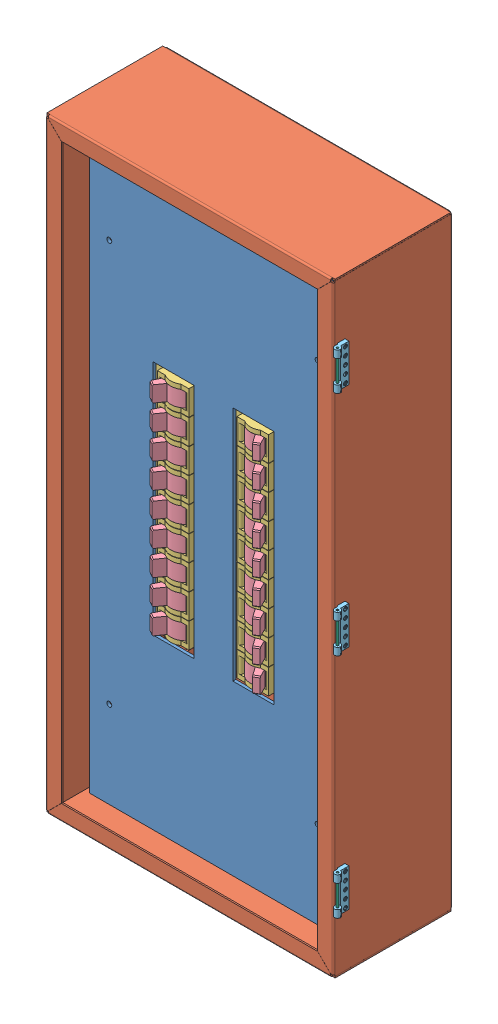
SolidWorks assembly Panel Assembly, configuration Default. Lengths in mm.
Overall size (297.46 610.06 123.23).
65 component instances, 7 part files, 17 mates.
Components (placement in the parent):
- M-P-001-1: M-P-001 [Default] at (-145.2279 305.0279 96.0279) x (1 0 0) z (0 -1 0) size (250 3 580)
- M-P-002-Base Panel Model-1: M-P-002-Base Panel Model [Default] at (-145.2279 305.0279 0.2279) size (290.46 610.06 120.23)
- M-P-003-Breaker Model-1: M-P-003-Breaker Model [Default] at (-185.3529 418.6279 96.5889) x (0 -1 0) z (-1 0 0) size (25 111.98 84.5)
  - M-P-003-Breaker Model Base-1: M-P-003-Breaker Model Base [Default] at origin size (25 97.4 84.5)
  - M-P-003-Breaker Model Switch-1: M-P-003-Breaker Model Switch [Default] at (4.5 -12.67 0) x (1 0 0) z (0 -0.508856 0.860852) size (16 40.5 30)
- M-P-003-Breaker Model-2: M-P-003-Breaker Model [Default] at (-185.3529 393.2279 96.5889) x (0 -1 0) z (-1 0 0) size (25 111.98 84.5)
  - M-P-003-Breaker Model Base-1: M-P-003-Breaker Model Base [Default] at origin size (25 97.4 84.5)
  - M-P-003-Breaker Model Switch-1: M-P-003-Breaker Model Switch [Default] at (4.5 -12.67 0) x (1 0 0) z (0 -0.508856 0.860852) size (16 40.5 30)
- M-P-003-Breaker Model-3: M-P-003-Breaker Model [Default] at (-185.3529 367.8279 96.5889) x (0 -1 0) z (-1 0 0) size (25 111.98 84.5)
  - M-P-003-Breaker Model Base-1: M-P-003-Breaker Model Base [Default] at origin size (25 97.4 84.5)
  - M-P-003-Breaker Model Switch-1: M-P-003-Breaker Model Switch [Default] at (4.5 -12.67 0) x (1 0 0) z (0 -0.508856 0.860852) size (16 40.5 30)
- M-P-003-Breaker Model-4: M-P-003-Breaker Model [Default] at (-185.3529 342.4279 96.5889) x (0 -1 0) z (-1 0 0) size (25 111.98 84.5)
  - M-P-003-Breaker Model Base-1: M-P-003-Breaker Model Base [Default] at origin size (25 97.4 84.5)
  - M-P-003-Breaker Model Switch-1: M-P-003-Breaker Model Switch [Default] at (4.5 -12.67 0) x (1 0 0) z (0 -0.508856 0.860852) size (16 40.5 30)
- M-P-003-Breaker Model-5: M-P-003-Breaker Model [Default] at (-185.3529 317.0279 96.5889) x (0 -1 0) z (-1 0 0) size (25 111.98 84.5)
  - M-P-003-Breaker Model Base-1: M-P-003-Breaker Model Base [Default] at origin size (25 97.4 84.5)
  - M-P-003-Breaker Model Switch-1: M-P-003-Breaker Model Switch [Default] at (4.5 -12.67 0) x (1 0 0) z (0 -0.508856 0.860852) size (16 40.5 30)
- M-P-003-Breaker Model-6: M-P-003-Breaker Model [Default] at (-185.3529 291.6279 96.5889) x (0 -1 0) z (-1 0 0) size (25 111.98 84.5)
  - M-P-003-Breaker Model Base-1: M-P-003-Breaker Model Base [Default] at origin size (25 97.4 84.5)
  - M-P-003-Breaker Model Switch-1: M-P-003-Breaker Model Switch [Default] at (4.5 -12.67 0) x (1 0 0) z (0 -0.508856 0.860852) size (16 40.5 30)
- M-P-003-Breaker Model-7: M-P-003-Breaker Model [Default] at (-185.3529 266.2279 96.5889) x (0 -1 0) z (-1 0 0) size (25 111.98 84.5)
  - M-P-003-Breaker Model Base-1: M-P-003-Breaker Model Base [Default] at origin size (25 97.4 84.5)
  - M-P-003-Breaker Model Switch-1: M-P-003-Breaker Model Switch [Default] at (4.5 -12.67 0) x (1 0 0) z (0 -0.508856 0.860852) size (16 40.5 30)
- M-P-003-Breaker Model-8: M-P-003-Breaker Model [Default] at (-185.3529 240.8279 96.5889) x (0 -1 0) z (-1 0 0) size (25 111.98 84.5)
  - M-P-003-Breaker Model Base-1: M-P-003-Breaker Model Base [Default] at origin size (25 97.4 84.5)
  - M-P-003-Breaker Model Switch-1: M-P-003-Breaker Model Switch [Default] at (4.5 -12.67 0) x (1 0 0) z (0 -0.508856 0.860852) size (16 40.5 30)
- M-P-003-Breaker Model-9: M-P-003-Breaker Model [Default] at (-185.3529 215.4279 96.5889) x (0 -1 0) z (-1 0 0) size (25 111.98 84.5)
  - M-P-003-Breaker Model Base-1: M-P-003-Breaker Model Base [Default] at origin size (25 97.4 84.5)
  - M-P-003-Breaker Model Switch-1: M-P-003-Breaker Model Switch [Default] at (4.5 -12.67 0) x (1 0 0) z (0 -0.508856 0.860852) size (16 40.5 30)
- M-P-003-Breaker Model-10: M-P-003-Breaker Model [Default] at (-105.1029 393.6279 96.5889) x (0 1 0) z (1 0 0) size (25 111.98 84.5)
  - M-P-003-Breaker Model Base-1: M-P-003-Breaker Model Base [Default] at origin size (25 97.4 84.5)
  - M-P-003-Breaker Model Switch-1: M-P-003-Breaker Model Switch [Default] at (4.5 -12.67 0) x (1 0 0) z (0 -0.508856 0.860852) size (16 40.5 30)
- M-P-003-Breaker Model-11: M-P-003-Breaker Model [Default] at (-105.1029 368.2279 96.5889) x (0 1 0) z (1 0 0) size (25 111.98 84.5)
  - M-P-003-Breaker Model Base-1: M-P-003-Breaker Model Base [Default] at origin size (25 97.4 84.5)
  - M-P-003-Breaker Model Switch-1: M-P-003-Breaker Model Switch [Default] at (4.5 -12.67 0) x (1 0 0) z (0 -0.508856 0.860852) size (16 40.5 30)
- M-P-003-Breaker Model-12: M-P-003-Breaker Model [Default] at (-105.1029 342.8279 96.5889) x (0 1 0) z (1 0 0) size (25 111.98 84.5)
  - M-P-003-Breaker Model Base-1: M-P-003-Breaker Model Base [Default] at origin size (25 97.4 84.5)
  - M-P-003-Breaker Model Switch-1: M-P-003-Breaker Model Switch [Default] at (4.5 -12.67 0) x (1 0 0) z (0 -0.508856 0.860852) size (16 40.5 30)
- M-P-003-Breaker Model-13: M-P-003-Breaker Model [Default] at (-105.1029 317.4279 96.5889) x (0 1 0) z (1 0 0) size (25 111.98 84.5)
  - M-P-003-Breaker Model Base-1: M-P-003-Breaker Model Base [Default] at origin size (25 97.4 84.5)
  - M-P-003-Breaker Model Switch-1: M-P-003-Breaker Model Switch [Default] at (4.5 -12.67 0) x (1 0 0) z (0 -0.508856 0.860852) size (16 40.5 30)
- M-P-003-Breaker Model-14: M-P-003-Breaker Model [Default] at (-105.1029 292.0279 96.5889) x (0 1 0) z (1 0 0) size (25 111.98 84.5)
  - M-P-003-Breaker Model Base-1: M-P-003-Breaker Model Base [Default] at origin size (25 97.4 84.5)
  - M-P-003-Breaker Model Switch-1: M-P-003-Breaker Model Switch [Default] at (4.5 -12.67 0) x (1 0 0) z (0 -0.508856 0.860852) size (16 40.5 30)
- M-P-003-Breaker Model-15: M-P-003-Breaker Model [Default] at (-105.1029 266.6279 96.5889) x (0 1 0) z (1 0 0) size (25 111.98 84.5)
  - M-P-003-Breaker Model Base-1: M-P-003-Breaker Model Base [Default] at origin size (25 97.4 84.5)
  - M-P-003-Breaker Model Switch-1: M-P-003-Breaker Model Switch [Default] at (4.5 -12.67 0) x (1 0 0) z (0 -0.508856 0.860852) size (16 40.5 30)
- M-P-003-Breaker Model-16: M-P-003-Breaker Model [Default] at (-105.1029 241.2279 96.5889) x (0 1 0) z (1 0 0) size (25 111.98 84.5)
  - M-P-003-Breaker Model Base-1: M-P-003-Breaker Model Base [Default] at origin size (25 97.4 84.5)
  - M-P-003-Breaker Model Switch-1: M-P-003-Breaker Model Switch [Default] at (4.5 -12.67 0) x (1 0 0) z (0 -0.508856 0.860852) size (16 40.5 30)
- M-P-003-Breaker Model-17: M-P-003-Breaker Model [Default] at (-105.1029 215.8279 96.5889) x (0 1 0) z (1 0 0) size (25 111.98 84.5)
  - M-P-003-Breaker Model Base-1: M-P-003-Breaker Model Base [Default] at origin size (25 97.4 84.5)
  - M-P-003-Breaker Model Switch-1: M-P-003-Breaker Model Switch [Default] at (4.5 -12.67 0) x (1 0 0) z (0 -0.508856 0.860852) size (16 40.5 30)
- M-P-003-Breaker Model-18: M-P-003-Breaker Model [Default] at (-105.1029 190.4279 96.5889) x (0 1 0) z (1 0 0) size (25 111.98 84.5)
  - M-P-003-Breaker Model Base-1: M-P-003-Breaker Model Base [Default] at origin size (25 97.4 84.5)
  - M-P-003-Breaker Model Switch-1: M-P-003-Breaker Model Switch [Default] at (4.5 -12.67 0) x (1 0 0) z (0 -0.508856 0.860852) size (16 40.5 30)
- M-D-009-Hinge Flap 2-1: M-D-009-Hinge Flap 2 [Default] at (4 515.0558 120.2279) x (0 0 1) z (-1 0 0) size (14.5 38 7)
- M-D-007-Hinge Pin-1: M-D-007-Hinge Pin [Default] at (6.0444 540.4437 115.2928) size (2 38 2)
- M-D-009-Hinge Flap 2-2: M-D-009-Hinge Flap 2 [Default] at (4 286.0279 120.2279) x (0 0 1) z (-1 0 0) size (14.5 38 7)
- M-D-009-Hinge Flap 2-3: M-D-009-Hinge Flap 2 [Default] at (4 57 120.2279) x (0 0 1) z (-1 0 0) size (14.5 38 7)
- M-D-007-Hinge Pin-2: M-D-007-Hinge Pin [Default] at (6.0444 311.4158 115.2928) size (2 38 2)
- M-D-007-Hinge Pin-3: M-D-007-Hinge Pin [Default] at (6.0444 82.3879 115.2928) size (2 38 2)
- M-D-010-Hinge Mounting Bar-1: M-D-010-Hinge Mounting Bar [Default] at (-1.5189 526.0558 99.1779) x (0 1 0) z (-1 0 0) size (63.5 38.1 12.7)
- M-D-010-Hinge Mounting Bar-2: M-D-010-Hinge Mounting Bar [Default] at (-1.5189 297.2558 99.1779) x (0 1 0) z (-1 0 0) size (63.5 38.1 12.7)
- M-D-010-Hinge Mounting Bar-3: M-D-010-Hinge Mounting Bar [Default] at (-1.5189 68.4558 99.1779) x (0 1 0) z (-1 0 0) size (63.5 38.1 12.7)
Mates (geometry in assembly coordinates):
- Width1: width aligned: plane of M-P-001-1 through (-270.2279 15.0279 -538.5574) normal (-1 0 0); plane of M-P-001-1 through (-20.2279 15.0279 -538.5574) normal (1 0 0); plane of M-P-002-Base Panel Model-1 through (-1.5189 0.2279 120.2279) normal (-1 0 0); plane of M-P-002-Base Panel Model-1 through (-288.9369 0.2279 120.2279) normal (1 0 0)
- Width2: width anti-aligned: plane of M-P-001-1 through (-270.2279 15.0279 -538.5574) normal (0 -1 0); plane of M-P-001-1 through (-270.2279 595.0279 -538.5574) normal (0 1 0); plane of M-P-002-Base Panel Model-1 through (-290.2279 610.0558 120.2279) normal (0 1 0); plane of M-P-002-Base Panel Model-1 through (-290.2279 0 120.2279) normal (0 -1 0)
- Coincident1: coincident anti-aligned: plane of M-P-001-1 through (-145.2279 305.0279 93.0279) normal (0 0 -1); plane of M-P-002-Base Panel Model-1 through (-145.2279 305.0279 93.0279) normal (0 0 1)
- Coincident28: coincident anti-aligned: plane of M-P-002-Base Panel Model-1 through (-145.2279 305.0279 0) normal (0 0 -1)
- Coincident29: coincident anti-aligned: plane of M-P-002-Base Panel Model-1 through (-290.2279 0 120.2279) normal (0 -1 0)
- Coincident30: coincident aligned: plane of M-P-002-Base Panel Model-1 through (0 0.2279 120.2279) normal (1 0 0)
- Width8: width anti-aligned: plane of M-P-003-Breaker Model-1/M-P-003-Breaker Model Base-1 through (-201.2279 393.6279 90.4189) normal (-1 0 0); plane of M-P-003-Breaker Model-1/M-P-003-Breaker Model Base-1 through (-169.4779 393.6279 96.5889) normal (1 0 0); plane of M-P-001-1 through (-205.9779 423.6279 93.0279) normal (1 0 0); plane of M-P-001-1 through (-164.7279 423.6279 93.0279) normal (-1 0 0)
- Distance5: distance = 5 mm anti-aligned: plane of M-P-003-Breaker Model-1/M-P-003-Breaker Model Base-1 through (-185.3529 418.6279 96.5889) normal (0 1 0); plane of M-P-001-1 through (-205.9779 423.6279 93.0279) normal (0 -1 0)
- Coincident31: coincident anti-aligned: plane of M-P-002-Base Panel Model-1 through (-145.2279 305.0279 1.5189) normal (0 0 1); plane of M-P-003-Breaker Model-1/M-P-003-Breaker Model Base-1 through (-145.7279 393.6279 1.5189) normal (0 0 -1)
- Concentric1: concentric anti-aligned: circle of M-D-009-Hinge Flap 2-1; circle of M-P-002-Base Panel Model-1
- Concentric2: concentric anti-aligned: circle of M-P-002-Base Panel Model-1; circle of M-D-009-Hinge Flap 2-1
- Coincident32: coincident anti-aligned: plane of M-P-002-Base Panel Model-1 through (0 0.2279 120.2279) normal (1 0 0); plane of M-D-009-Hinge Flap 2-1 through (0 553.0558 120.2279) normal (-1 0 0)
- Concentric3: concentric aligned: cylinder of M-D-009-Hinge Flap 2-1 through (4 553.0558 120.2279) axis (0 -1 0) radius 1; cylinder of M-D-007-Hinge Pin-1 through (4 553.0558 120.2279) axis (0 -1 0) radius 1
- Coincident33: coincident aligned: plane of M-D-009-Hinge Flap 2-1 through (4 553.0558 120.2279) normal (0 1 0); plane of M-D-007-Hinge Pin-1 through (4.9 553.0558 120.2279) normal (0 1 0)
- Concentric4: concentric anti-aligned: cylinder of M-P-002-Base Panel Model-1 through (0 550.0558 112.2279) axis (1 0 0) radius 2.25; cylinder of M-D-010-Hinge Mounting Bar-1 through (-14.2189 550.0558 112.2279) axis (-1 0 0) radius 2.25
- Concentric5: concentric anti-aligned: cylinder of M-P-002-Base Panel Model-1 through (0 518.0558 112.2279) axis (1 0 0) radius 2.25; cylinder of M-D-010-Hinge Mounting Bar-1 through (-14.2189 518.0558 112.2279) axis (-1 0 0) radius 2.25
- Coincident34: coincident anti-aligned: plane of M-P-002-Base Panel Model-1 through (-1.5189 0.2279 120.2279) normal (-1 0 0); plane of M-D-010-Hinge Mounting Bar-1 through (-1.5189 526.0558 99.1779) normal (1 0 0)
